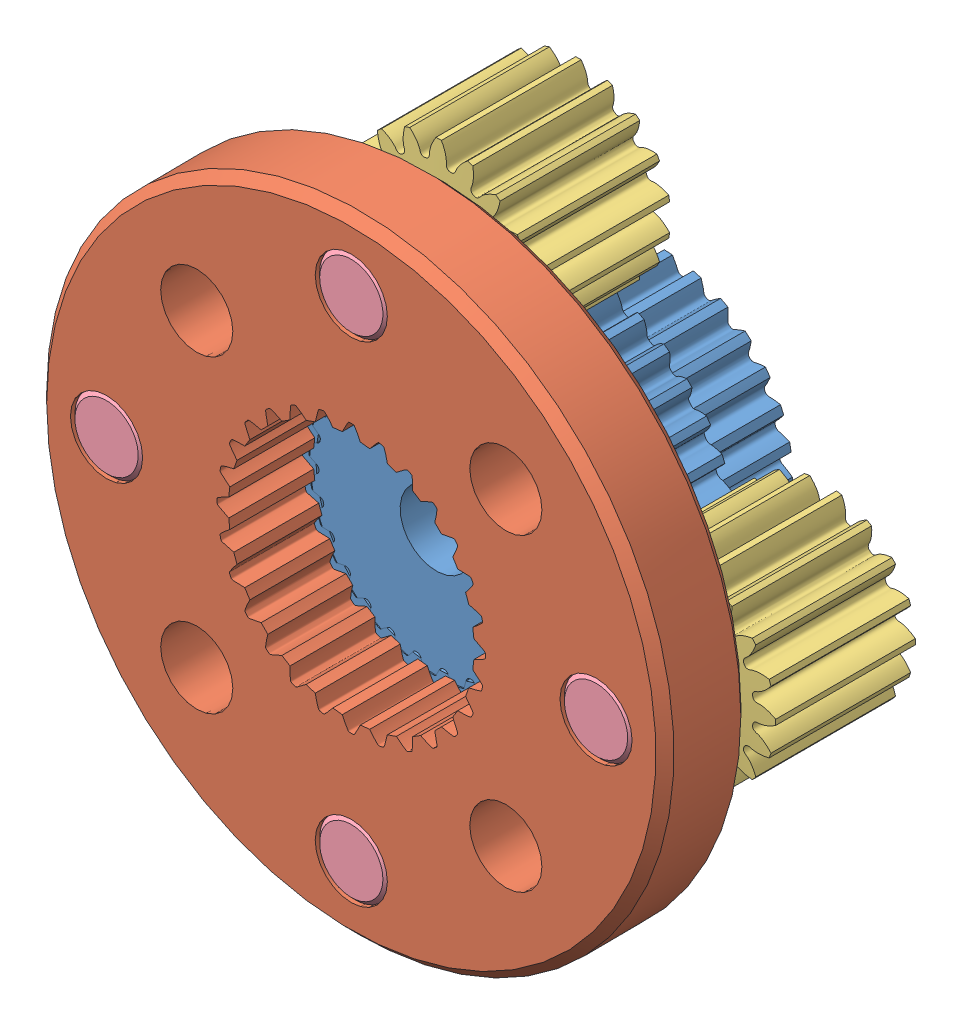
SolidWorks assembly 217-2817-STEP, configuration Default. Lengths in mm.
Overall size (37.47 37.47 17.4).
10 component instances, 4 part files, 0 mates.
Components (placement in the parent):
- 217-2724-001 Rev1_Sun_Driver01-1: 217-2724-001 Rev1_Sun_Driver01 [Default] at (0 0 -6.375) x (0.984808 0.173648 0) z (0 0 1) size (18.94 18.95 12.7)
- 217-2724-002 Rev1-1: 217-2724-002 Rev1 [Default] at (0 0 -2.35) x (0 1 0) z (0 0 1) size (34.7 34.7 4.7)
- 217-2724-003 Rev1_Planet_Revolving_Follower01-1: 217-2724-003 Rev1_Planet_Revolving_Follower01 [Default] at (0 13.5382 -8.7) x (-1 0 0) z (0 0 1) size (10.3 10.39 8.06)
- 217-2625-010 Rev1-1: 217-2625-010 Rev1 [Default] at (0 13.5382 -6) x (0.999987 -0.005082 0) z (0 0 1) size (4 4 12)
- 217-2625-010 Rev1-2: 217-2625-010 Rev1 [Default] at (13.5382 0 -6) x (-0.005082 -0.999987 0) z (0 0 1) size (4 4 12)
- 217-2625-010 Rev1-3: 217-2625-010 Rev1 [Default] at (0 -13.5382 -6) x (-0.999987 0.005082 0) z (0 0 1) size (4 4 12)
- 217-2625-010 Rev1-4: 217-2625-010 Rev1 [Default] at (-13.5382 0 -6) x (0.005082 0.999987 0) z (0 0 1) size (4 4 12)
- 217-2724-003 Rev1_Planet_Revolving_Follower01-2: 217-2724-003 Rev1_Planet_Revolving_Follower01 [Default] at (13.5382 0 -8.7) x (0 1 0) z (0 0 1) size (10.3 10.39 8.06)
- 217-2724-003 Rev1_Planet_Revolving_Follower01-3: 217-2724-003 Rev1_Planet_Revolving_Follower01 [Default] at (0 -13.5382 -8.7) size (10.3 10.39 8.06)
- 217-2724-003 Rev1_Planet_Revolving_Follower01-4: 217-2724-003 Rev1_Planet_Revolving_Follower01 [Default] at (-13.5382 0 -8.7) x (0 -1 0) z (0 0 1) size (10.3 10.39 8.06)
